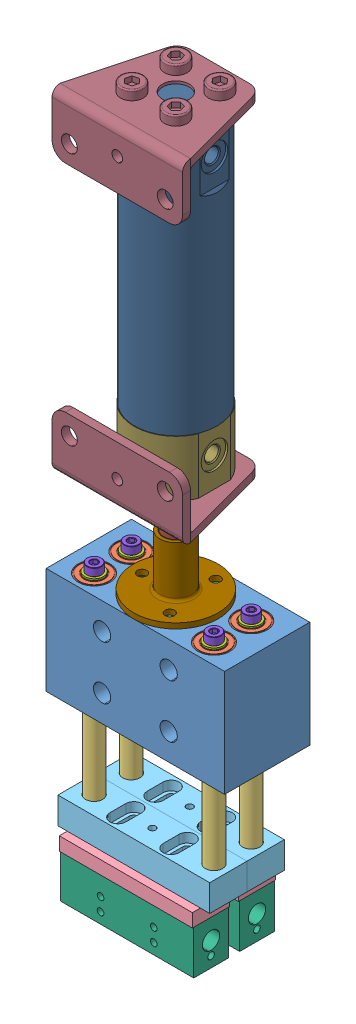
SolidWorks assembly SEALER, configuration Default. Lengths in mm.
Overall size (67 272.53 42.83).
31 component instances, 14 part files, 58 mates.
Components (placement in the parent):
- BUSHING HOLDER-1: BUSHING HOLDER [Default] at (0 0 -32) x (-1 0 0) z (0 0 1) size (67 40 32)
- 61205K74_Fixed Alignment Linear Ball Bearing-1: 61205K74_Fixed Alignment Linear Ball Bearing [61205K74] at (-56.5 -9.5 -7.5) x (0.847576 0 -0.530675) z (0 -1 0) size (12 12 19)
- 61205K74_Fixed Alignment Linear Ball Bearing-2: 61205K74_Fixed Alignment Linear Ball Bearing [61205K74] at (-56.5 -9.5 -21.5) x (0.412503 0 0.910956) z (0 1 0) size (12 12 19)
- 61205K74_Fixed Alignment Linear Ball Bearing-3: 61205K74_Fixed Alignment Linear Ball Bearing [61205K74] at (-11.5 -9.5 -7.5) x (0.727586 0 0.686017) z (0 1 0) size (12 12 19)
- 61205K74_Fixed Alignment Linear Ball Bearing-4: 61205K74_Fixed Alignment Linear Ball Bearing [61205K74] at (-11.5 -9.5 -21.5) x (-0.556494 0 0.830852) z (0 1 0) size (12 12 19)
- 7417N11_Internally Threaded Connecting Rod-1: 7417N11_Internally Threaded Connecting Rod [7417N11] at (-56.5 -37.5 -7.5) x (-0.904736 0 -0.425973) z (0 -1 0) size (6.3 6.3 75)
- 7417N11_Internally Threaded Connecting Rod-2: 7417N11_Internally Threaded Connecting Rod [7417N11] at (-56.5 -37.5 -21.5) x (0.429492 0 0.903071) z (0 -1 0) size (6.3 6.3 75)
- 7417N11_Internally Threaded Connecting Rod-3: 7417N11_Internally Threaded Connecting Rod [7417N11] at (-11.5 -37.5 -7.5) x (-0.255212 0 -0.966885) z (0 -1 0) size (6.3 6.3 75)
- 7417N11_Internally Threaded Connecting Rod-4: 7417N11_Internally Threaded Connecting Rod [7417N11] at (-11.5 -37.5 -21.5) x (0.999698 0 0.024563) z (0 -1 0) size (6.3 6.3 75)
- INSULATION-1: INSULATION [Default] at (-34.59 -84.5 -4.5) x (1 0 0) z (0 -1 0) size (50 14 5)
- HEATER HOLDER-1: HEATER HOLDER [Default] at (-34.59 -82 -7.5) x (1 0 0) z (0 1 0) size (57 14 10)
- HEATER HOLDER-2: HEATER HOLDER [Default] at (-34.59 -82 -21.5) x (1 0 0) z (0 1 0) size (57 14 10)
- INSULATION-2: INSULATION [Default] at (-34.59 -84.5 -21.75) x (1 0 0) z (0 -1 0) size (50 14 5)
- HEATER-1: HEATER [Default] at (-34.59 -95.25 -21.75) x (-1 0 0) z (0 0 -1) size (50 18.5 13)
- HEATER-2: HEATER [Default] at (-34.59 -95.25 -4.5) size (50 18.5 13)
- 93475A210_18-8 Stainless Steel Washer-1: 93475A210_18-8 Stainless Steel Washer [93475A210] at (-11.5 0 -21.5) x (0.99865 0 -0.051948) z (0 1 0) size (7 7 0.6)
- 91290A117_Alloy Steel Socket Head Screw-1: 91290A117_Alloy Steel Socket Head Screw [91290A117] at (-11.5 -3.9 -21.5) x (0.608197 0 0.793786) z (0 1 0) size (5.5 5.5 15.14)
- 93475A210_18-8 Stainless Steel Washer-3: 93475A210_18-8 Stainless Steel Washer [93475A210] at (-56.5 0 -7.5) x (-0.733009 0 -0.680219) z (0 1 0) size (7 7 0.6)
- 93475A210_18-8 Stainless Steel Washer-4: 93475A210_18-8 Stainless Steel Washer [93475A210] at (-56.5 0 -21.5) x (-0.155154 0 0.98789) z (0 1 0) size (7 7 0.6)
- 93475A210_18-8 Stainless Steel Washer-5: 93475A210_18-8 Stainless Steel Washer [93475A210] at (-11.5 0.6 -7.5) x (-0.630467 0 -0.776216) z (0 -1 0) size (7 7 0.6)
- 91290A117_Alloy Steel Socket Head Screw-5: 91290A117_Alloy Steel Socket Head Screw [91290A117] at (-11.5 -3.9 -7.5) x (0.546986 0 0.837142) z (0 1 0) size (5.5 5.5 15.14)
- 91290A117_Alloy Steel Socket Head Screw-6: 91290A117_Alloy Steel Socket Head Screw [91290A117] at (-56.5 -3.9 -21.5) x (0.988775 0 -0.149413) z (0 1 0) size (5.5 5.5 15.14)
- 91290A117_Alloy Steel Socket Head Screw-7: 91290A117_Alloy Steel Socket Head Screw [91290A117] at (-56.5 -3.9 -7.5) x (0.999333 0 0.036516) z (0 1 0) size (5.5 5.5 15.14)
- 90611A119_Screw-Mount Nut-1: 90611A119_Screw-Mount Nut [90611A119] at (-34.1714 0 -15.875) x (0.919961 0 0.39201) z (0 1 0) size (31.75 31.75 22.34)
- CG1LN25-25SZ-V-1: CG1LN25-25SZ-V [CG1LN25-25SZ-V] at (-34.1714 111.5344 -15.875) x (-1 0 0) z (0 -1 0) size (49 38.5 165.5)
  - CG1LN25-25SZ-V_CG1_Cylinder-1: CG1LN25-25SZ-V_CG1_Cylinder [25] at origin size (31 31 100)
  - CG1LN25-25SZ-V_CG1_Rod-1: CG1LN25-25SZ-V_CG1_Rod [25] at (0 0 -17.5) size (20 20 127.5)
  - CG1LN25-25SZ-V_CG1_End_Cap-1: CG1LN25-25SZ-V_CG1_End_Cap [25BN] at (0 0 49) size (29 31.4 23)
  - CG1LN25-25SZ-V_CG1_Rod_End_Nut-1: CG1LN25-25SZ-V_CG1_Rod_End_Nut [25] at (0 0 102) size (19.63 17 6.02) (hidden)
  - CG1LN25-25SZ-V_CG1_Foot-1: CG1LN25-25SZ-V_CG1_Foot [25] at (0 -22 73) size (49 38.5 25.5)
  - CG1LN25-25SZ-V_CG1_Foot-2: CG1LN25-25SZ-V_CG1_Foot [25] at (0 -22 -52) x (-1 0 0) z (0 0 -1) size (49 38.5 25.5)
Mates (geometry in assembly coordinates):
- Coincident2: coincident aligned: plane of BUSHING HOLDER-1 through (0 0 0) normal (0 1 0)
- Coincident3: coincident aligned: plane of BUSHING HOLDER-1 through (0 0 0) normal (0 0 1)
- Coincident4: coincident aligned: plane of BUSHING HOLDER-1 through (0 0 0) normal (1 0 0)
- Concentric1: concentric anti-aligned: cylinder of BUSHING HOLDER-1 through (-56.5 -19 -7.5) axis (0 1 0) radius 6; cylinder of 61205K74_Fixed Alignment Linear Ball Bearing-1 through (-56.5 -19 -7.5) axis (0 -1 0) radius 6
- Coincident5: coincident anti-aligned: circle of BUSHING HOLDER-1; circle of 61205K74_Fixed Alignment Linear Ball Bearing-1
- Concentric21: concentric anti-aligned: cylinder of BUSHING HOLDER-1 through (-56.5 -40 -21.5) axis (0 1 0) radius 4; cylinder of 61205K74_Fixed Alignment Linear Ball Bearing-2 through (-56.5 -18.82 -21.5) axis (0 -1 0) radius 3.93
- Coincident61: coincident anti-aligned: plane of BUSHING HOLDER-1 through (-56.5 -19 -21.5) normal (0 1 0); plane of 61205K74_Fixed Alignment Linear Ball Bearing-2 through (-51.0343 -19 -23.975) normal (0 -1 0)
- Concentric31: concentric anti-aligned: cylinder of BUSHING HOLDER-1 through (-11.5 -19 -7.5) axis (0 1 0) radius 6; cylinder of 61205K74_Fixed Alignment Linear Ball Bearing-3 through (-11.5 -18.82 -7.5) axis (0 -1 0) radius 3.93
- Coincident71: coincident anti-aligned: plane of BUSHING HOLDER-1 through (-11.5 -19 -7.5) normal (0 1 0); plane of 61205K74_Fixed Alignment Linear Ball Bearing-3 through (-7.3839 -19 -11.8655) normal (0 -1 0)
- Concentric41: concentric anti-aligned: cylinder of BUSHING HOLDER-1 through (-11.5 -40 -21.5) axis (0 1 0) radius 4; cylinder of 61205K74_Fixed Alignment Linear Ball Bearing-4 through (-11.5 -18.82 -21.5) axis (0 -1 0) radius 5.4
- Coincident81: coincident anti-aligned: plane of BUSHING HOLDER-1 through (-11.5 -19 -21.5) normal (0 1 0); plane of 61205K74_Fixed Alignment Linear Ball Bearing-4 through (-6.5149 -19 -18.161) normal (0 -1 0)
- Concentric5: concentric anti-aligned: circle of 61205K74_Fixed Alignment Linear Ball Bearing-1; cylinder of 7417N11_Internally Threaded Connecting Rod-1 through (-56.5 -63 -7.5) axis (0 1 0) radius 3.15
- Concentric61: concentric aligned: cylinder of 61205K74_Fixed Alignment Linear Ball Bearing-2 through (-56.5 0 -21.5) axis (0 1 0) radius 3.225; cylinder of 7417N11_Internally Threaded Connecting Rod-2 through (-56.5 -63 -21.5) axis (0 1 0) radius 3.15
- Concentric71: concentric aligned: cylinder of 61205K74_Fixed Alignment Linear Ball Bearing-4 through (-11.5 0 -21.5) axis (0 1 0) radius 3.225; cylinder of 7417N11_Internally Threaded Connecting Rod-4 through (-11.5 -63 -21.5) axis (0 1 0) radius 3.15
- Concentric8: concentric aligned: circle of 61205K74_Fixed Alignment Linear Ball Bearing-3; cylinder of 7417N11_Internally Threaded Connecting Rod-3 through (-11.5 -63 -7.5) axis (0 1 0) radius 3.15
- Coincident83: coincident aligned: plane of 7417N11_Internally Threaded Connecting Rod-1 through (-55.861 0 -8.8571) normal (0 1 0); plane of 7417N11_Internally Threaded Connecting Rod-2 through (-57.8546 0 -20.8558) normal (0 1 0)
- Coincident84: coincident aligned: plane of 7417N11_Internally Threaded Connecting Rod-3 through (-10.0497 0 -7.8828) normal (0 1 0); plane of 7417N11_Internally Threaded Connecting Rod-4 through (-11.5368 0 -20.0005) normal (0 1 0)
- Coincident85: coincident aligned: plane of 7417N11_Internally Threaded Connecting Rod-1 through (-55.861 0 -8.8571) normal (0 1 0); plane of 7417N11_Internally Threaded Connecting Rod-3 through (-10.0497 0 -7.8828) normal (0 1 0)
- Concentric72: concentric aligned: cylinder of HEATER HOLDER-1 through (-56.5 -72 -7.5) axis (0 1 0) radius 1.7; circle of 7417N11_Internally Threaded Connecting Rod-1
- Concentric73: concentric aligned: cylinder of HEATER HOLDER-1 through (-11.5 -72 -7.5) axis (0 1 0) radius 1.7; circle of 7417N11_Internally Threaded Connecting Rod-3
- Coincident86: coincident anti-aligned: plane of 7417N11_Internally Threaded Connecting Rod-3 through (-8.4543 -75 -8.3039) normal (0 -1 0); plane of HEATER HOLDER-1 through (-9.8 -75 -7.5) normal (0 1 0)
- Concentric74: concentric aligned: cylinder of HEATER HOLDER-2 through (-56.5 -72 -21.5) axis (0 1 0) radius 1.7; circle of 7417N11_Internally Threaded Connecting Rod-2
- Concentric75: concentric aligned: cylinder of HEATER HOLDER-2 through (-11.5 -72 -21.5) axis (0 1 0) radius 1.7; circle of 7417N11_Internally Threaded Connecting Rod-4
- Coincident87: coincident anti-aligned: plane of 7417N11_Internally Threaded Connecting Rod-4 through (-11.5774 -75 -18.351) normal (0 -1 0); plane of HEATER HOLDER-2 through (-9.8 -75 -21.5) normal (0 1 0)
- Coincident88: coincident anti-aligned: plane of HEATER HOLDER-2 through (-34.59 -82 -21.5) normal (0 -1 0); plane of INSULATION-2 through (-34.59 -82 -21.75) normal (0 1 0)
- Concentric78: concentric anti-aligned: cylinder of INSULATION-1 through (-44.59 -87 -4.5) axis (0 -1 0) radius 1.65; cylinder of HEATER HOLDER-1 through (-44.59 -82 -4.5) axis (0 1 0) radius 1.75
- Concentric79: concentric anti-aligned: cylinder of INSULATION-1 through (-24.59 -87 -4.5) axis (0 -1 0) radius 1.65; cylinder of HEATER HOLDER-1 through (-24.59 -82 -4.5) axis (0 1 0) radius 1.75
- Coincident89: coincident anti-aligned: plane of INSULATION-1 through (-34.59 -82 -4.5) normal (0 1 0); plane of HEATER HOLDER-1 through (-34.59 -82 -7.5) normal (0 -1 0)
- Concentric81: concentric anti-aligned: cylinder of INSULATION-2 through (-24.59 -87 -21.75) axis (0 -1 0) radius 1.65; cylinder of HEATER-1 through (-24.59 -87 -21.75) axis (0 1 0) radius 1.25
- Coincident90: coincident anti-aligned: plane of INSULATION-2 through (-34.59 -87 -21.75) normal (0 -1 0); plane of HEATER-1 through (-9.59 -87 -28.25) normal (0 1 0)
- Concentric82: concentric anti-aligned: cylinder of INSULATION-1 through (-44.59 -87 -4.5) axis (0 -1 0) radius 1.65; cylinder of HEATER-2 through (-44.59 -87 -4.5) axis (0 1 0) radius 1.25
- Concentric83: concentric anti-aligned: cylinder of INSULATION-1 through (-24.59 -87 -4.5) axis (0 -1 0) radius 1.65; cylinder of HEATER-2 through (-24.59 -87 -4.5) axis (0 1 0) radius 1.25
- Coincident91: coincident anti-aligned: plane of INSULATION-1 through (-34.59 -87 -4.5) normal (0 -1 0); plane of HEATER-2 through (-59.59 -87 2) normal (0 1 0)
- Parallel2: parallel aligned: plane of INSULATION-2 through (-59.59 -87 -28.75) normal (0 0 -1); plane of HEATER-1 through (-34.59 -95.25 -28.25) normal (0 0 -1)
- Distance1: distance = 3.25 mm anti-aligned: plane of INSULATION-2 through (-59.59 -87 -14.75) normal (0 0 1); plane of INSULATION-1 through (-59.59 -87 -11.5) normal (0 0 -1)
- Coincident95: coincident aligned: plane of INSULATION-1 through (-9.59 -87 -11.5) normal (1 0 0); plane of INSULATION-2 through (-9.59 -87 -28.75) normal (1 0 0)
- Concentric85: concentric aligned: circle of 93475A210_18-8 Stainless Steel Washer-1; circle of 7417N11_Internally Threaded Connecting Rod-4
- Coincident96: coincident anti-aligned: plane of 61205K74_Fixed Alignment Linear Ball Bearing-4 through (-8.8205 0 -19.7053) normal (0 1 0); plane of 93475A210_18-8 Stainless Steel Washer-1 through (-11.5 0 -21.5) normal (0 -1 0)
- Concentric86: concentric anti-aligned: circle of 93475A210_18-8 Stainless Steel Washer-1; cylinder of 91290A117_Alloy Steel Socket Head Screw-1 through (-11.5 -11.4 -21.5) axis (0 -1 0) radius 1.5
- Coincident97: coincident anti-aligned: plane of 93475A210_18-8 Stainless Steel Washer-1 through (-11.5 0.6 -21.5) normal (0 1 0); plane of 91290A117_Alloy Steel Socket Head Screw-1 through (-9.4362 0.6 -23.0813) normal (0 -1 0)
- Coincident991: coincident anti-aligned: plane of 7417N11_Internally Threaded Connecting Rod-1 through (-55.861 0 -8.8571) normal (0 1 0); plane of 93475A210_18-8 Stainless Steel Washer-3 through (-56.5 0 -7.5) normal (0 -1 0)
- Concentric89: concentric aligned: circle of 7417N11_Internally Threaded Connecting Rod-1; circle of 93475A210_18-8 Stainless Steel Washer-3
- Coincident1021: coincident anti-aligned: plane of 7417N11_Internally Threaded Connecting Rod-2 through (-57.8546 0 -20.8558) normal (0 1 0); plane of 93475A210_18-8 Stainless Steel Washer-4 through (-56.5 0 -21.5) normal (0 -1 0)
- Concentric90: concentric anti-aligned: circle of 7417N11_Internally Threaded Connecting Rod-2; cylinder of 93475A210_18-8 Stainless Steel Washer-4 through (-56.5 0.6 -21.5) axis (0 -1 0) radius 1.6
- Coincident1022: coincident anti-aligned: plane of 7417N11_Internally Threaded Connecting Rod-4 through (-11.5368 0 -20.0005) normal (0 1 0); plane of 93475A210_18-8 Stainless Steel Washer-1 through (-11.5 0 -21.5) normal (0 -1 0)
- Coincident10231: coincident anti-aligned: plane of 7417N11_Internally Threaded Connecting Rod-3 through (-10.0497 0 -7.8828) normal (0 1 0); plane of 93475A210_18-8 Stainless Steel Washer-5 through (-11.5 0 -7.5) normal (0 -1 0)
- Concentric913: concentric anti-aligned: cylinder of 7417N11_Internally Threaded Connecting Rod-3 through (-11.5 -63 -7.5) axis (0 1 0) radius 1.5; cylinder of 91290A117_Alloy Steel Socket Head Screw-5 through (-11.5 -11.4 -7.5) axis (0 -1 0) radius 1.5
- Coincident1027: coincident anti-aligned: plane of 93475A210_18-8 Stainless Steel Washer-5 through (-11.5 0.6 -7.5) normal (0 1 0); plane of 91290A117_Alloy Steel Socket Head Screw-5 through (-9.3234 0.6 -8.9222) normal (0 -1 0)
- Concentric914: concentric anti-aligned: cylinder of 7417N11_Internally Threaded Connecting Rod-2 through (-56.5 -63 -21.5) axis (0 1 0) radius 1.5; cylinder of 91290A117_Alloy Steel Socket Head Screw-6 through (-56.5 -11.4 -21.5) axis (0 -1 0) radius 1.5
- Coincident1028: coincident anti-aligned: plane of 93475A210_18-8 Stainless Steel Washer-4 through (-56.5 0.6 -21.5) normal (0 1 0); plane of 91290A117_Alloy Steel Socket Head Screw-6 through (-56.8885 0.6 -24.0708) normal (0 -1 0)
- Concentric915: concentric anti-aligned: cylinder of 7417N11_Internally Threaded Connecting Rod-1 through (-56.5 -63 -7.5) axis (0 1 0) radius 1.5; cylinder of 91290A117_Alloy Steel Socket Head Screw-7 through (-56.5 -11.4 -7.5) axis (0 -1 0) radius 1.5
- Coincident1029: coincident anti-aligned: plane of 93475A210_18-8 Stainless Steel Washer-3 through (-56.5 0.6 -7.5) normal (0 1 0); plane of 91290A117_Alloy Steel Socket Head Screw-7 through (-56.4051 0.6 -10.0983) normal (0 -1 0)
- Coincident10232: coincident anti-aligned: plane of BUSHING HOLDER-1 through (0 0 0) normal (0 1 0); plane of 90611A119_Screw-Mount Nut-1 through (-34.1714 0 -15.875) normal (0 -1 0)
- Tangent1: tangent: plane of BUSHING HOLDER-1 through (0 0 0) normal (0 0 1); circle of 90611A119_Screw-Mount Nut-1
- Concentric916: concentric anti-aligned: circle of BUSHING HOLDER-1; circle of 90611A119_Screw-Mount Nut-1
- Concentric917: concentric aligned: circle of 90611A119_Screw-Mount Nut-1; cylinder of CG1LN25-25SZ-V-1/CG1LN25-25SZ-V_CG1_Rod-1 through (-34.1714 -12.6078 -15.875) axis (0 1 0) radius 5
- Parallel3: parallel anti-aligned: plane of BUSHING HOLDER-1 through (0 0 -32) normal (0 0 -1); plane of CG1LN25-25SZ-V-1/CG1LN25-25SZ-V_CG1_Foot-1 through (-58.6714 38.5344 6.125) normal (0 0 1)
- Coincident10234: coincident aligned: plane of 90611A119_Screw-Mount Nut-1 through (-34.1714 21.0344 -15.875) normal (0 1 0); plane of CG1LN25-25SZ-V-1/CG1LN25-25SZ-V_CG1_Rod-1 through (-39.1714 21.0344 -15.875) normal (0 1 0)
